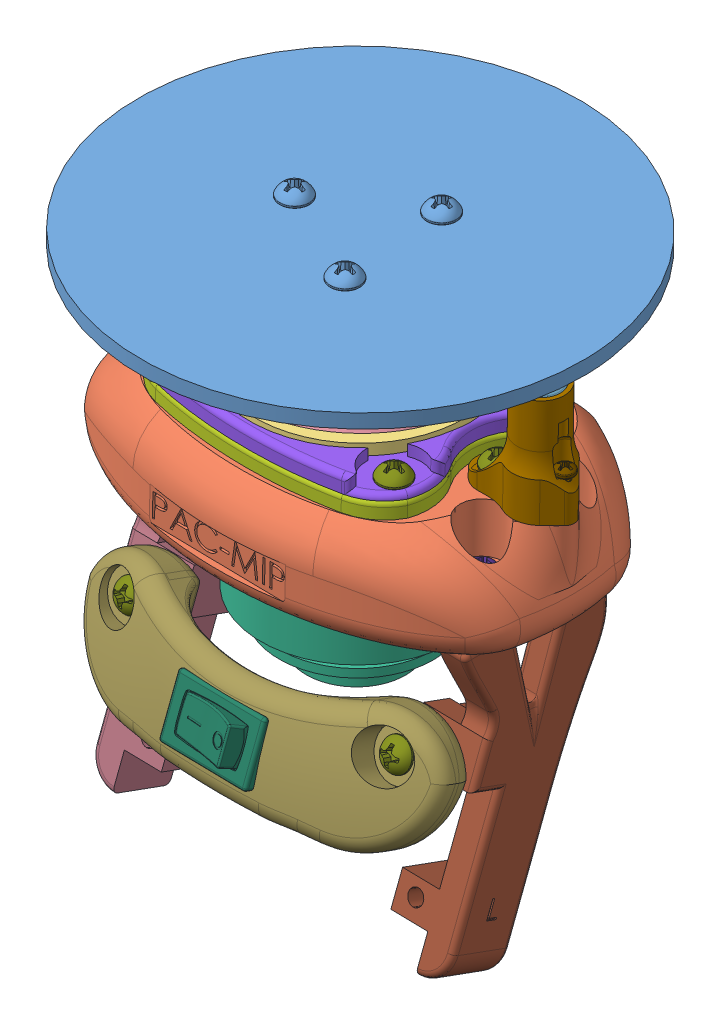
SolidWorks assembly POV, configuration Default. Lengths in mm.
Overall size (86.36 103.02 86.33).
31 component instances, 19 part files, 200 mates.
Components (placement in the parent):
- PCB disk-1: PCB disk [Default] at (29.9915 168.4081 -24.0716) x (-0.082505 0.001098 -0.99659) z (0.996507 -0.012889 -0.082512) size (80 2.79 80)
- Main Frame-1: Main Frame [Default] at (29.7154 147.0599 -24.0722) x (0.999905 -0.012935 0.004708) z (0.004708 -0.00003 -0.999989) size (81.15 20.06 65.6)
- Coil-1: Coil [Default] at (29.8104 154.4093 -24.072) x (0.99142 -0.012822 -0.130081) z (0.13007 -0.001713 0.991503) size (38 2 38)
- Top Coil Mount-1: Top Coil Mount [Default] at (29.8104 154.4093 -24.072) x (0.821748 -0.010613 -0.569753) z (0.012935 0.999916 0.00003) size (43 43 14)
- Motor Hub-1: Motor Hub [Default] at (29.7671 151.0596 -24.0721) x (-0.082505 0.001098 -0.99659) z (0.996507 -0.012889 -0.082512) size (27.61 6.35 25.31)
- Motor_pololu-37D-encoder-2: Motor_pololu-37D-encoder [Default] at (29.6895 145.0601 -24.0723) x (0.495875 -0.006441 0.86837) z (0.012935 0.999916 0.00003) size (34.8 34.8 48.55)
- Motor Mount-1: Motor Mount [Default] at (29.7283 148.0598 -24.0722) x (-0.999905 0.012935 -0.004708) z (-0.004708 0.00003 0.999989) size (48.16 8.83 46)
- Bottom Coil Mount-1: Bottom Coil Mount [Default] at (29.7671 151.0596 -24.0721) x (-0.999905 0.012935 -0.004708) z (-0.004708 0.00003 0.999989) size (48.16 8.83 50.89)
- Magnet Stand-1: Magnet Stand [Default] at (29.7154 147.0599 -24.0722) x (0.999905 -0.012935 0.004708) z (0.004708 -0.00003 -0.999989) size (71.91 19 65.6)
- Coil-2: Coil [Default] at (29.7412 149.0598 -24.0722) x (0.999916 -0.012935 0) z (0 -0.00003 1) size (38 2 38)
- Wire Mount-1: Wire Mount [Default] at (29.9527 165.4084 -24.0717) x (0.821748 -0.010613 -0.569753) z (0.012935 0.999916 0.00003) size (43 47.25 5.24)
- Left Support-1: Left Support [Default] at (28.6976 83.9425 -14.0477) x (0.999905 -0.012935 0.004708) z (0 0.34202 0.939693) size (13.46 57.62 28.85)
- Switch Mount-1: Switch Mount [Default] at (28.9937 75.8569 -66.442) x (0.999905 -0.012935 0.004708) z (0 0.34202 0.939693) size (65.39 22.18 13.95)
- Right Support-1: Right Support [Default] at (-36.2562 84.7828 -14.3535) x (0.999905 -0.012935 0.004708) z (0 0.34202 0.939693) size (13.46 57.62 28.85)
- Magnet-1: Magnet [Default] at (62.7063 161.6344 -23.9173) x (0.999916 -0.012935 0) z (0 -0.00003 1) size (7 2 7)
- Rocker Switch-1: Rocker Switch [Default] at (28.8816 105.0951 1.6459) x (0.013766 0.939604 -0.341988) z (0 0.34202 0.939693) size (10.55 15.93 19.4)
- 90279A110_ZNC PLTD STL ROUND HEAD PHILLIP MACHINE SCREW-1: 90279A110_ZNC PLTD STL ROUND HEAD PHILLIP MACHINE SCREW [90279A110] at (53.2759 108.8307 -7.6756) x (1 0 0) z (0 0.34202 0.939693) size (5.36 5.79 15.41)
- 90279A110_ZNC PLTD STL ROUND HEAD PHILLIP MACHINE SCREW-2: 90279A110_ZNC PLTD STL ROUND HEAD PHILLIP MACHINE SCREW [90279A110] at (5.0205 109.455 -7.9029) x (1 0 0) z (0 0.34202 0.939693) size (5.36 5.79 15.41)
- 90279A110_ZNC PLTD STL ROUND HEAD PHILLIP MACHINE SCREW-3: 90279A110_ZNC PLTD STL ROUND HEAD PHILLIP MACHINE SCREW [90279A110] at (49.6758 148.8015 -10.4782) x (0.999915 -0.012935 0.001662) z (0.012935 0.999916 0.00003) size (5.36 5.79 15.41)
- 90279A110_ZNC PLTD STL ROUND HEAD PHILLIP MACHINE SCREW-4: 90279A110_ZNC PLTD STL ROUND HEAD PHILLIP MACHINE SCREW [90279A110] at (49.8029 148.8006 -37.4779) x (-0.999843 0.012934 0.012152) z (0.012935 0.999916 0.00003) size (5.36 5.79 15.41)
- 90279A110_ZNC PLTD STL ROUND HEAD PHILLIP MACHINE SCREW-5: 90279A110_ZNC PLTD STL ROUND HEAD PHILLIP MACHINE SCREW [90279A110] at (9.6796 149.3189 -10.6665) x (-0.023578 0.000335 -0.999722) z (0.012935 0.999916 0.00003) size (5.36 5.79 15.41)
- 90279A110_ZNC PLTD STL ROUND HEAD PHILLIP MACHINE SCREW-6: 90279A110_ZNC PLTD STL ROUND HEAD PHILLIP MACHINE SCREW [90279A110] at (9.8067 149.3181 -37.6662) x (0.999916 -0.012935 0) z (0.012935 0.999916 0.00003) size (5.36 5.79 15.41)
- 90279A110_ZNC PLTD STL ROUND HEAD PHILLIP MACHINE SCREW-7: 90279A110_ZNC PLTD STL ROUND HEAD PHILLIP MACHINE SCREW [90279A110] at (55.013 146.7327 -23.9531) x (0.999833 -0.012934 -0.012935) z (0.012935 0.999916 0.00003) size (5.36 5.79 15.41)
- 90279A112_ZNC PLTD STL ROUND HEAD PHILLIP MACHINE SCREW-1: 90279A112_ZNC PLTD STL ROUND HEAD PHILLIP MACHINE SCREW [90279A112] at (59.5856 135.6728 -31.4313) x (0.999833 -0.012934 -0.012935) z (0.012935 0.999916 0.00003) size (5.36 5.79 18.6)
- 90279A112_ZNC PLTD STL ROUND HEAD PHILLIP MACHINE SCREW-2: 90279A112_ZNC PLTD STL ROUND HEAD PHILLIP MACHINE SCREW [90279A112] at (59.5149 135.6733 -16.4315) x (0.897955 -0.011603 -0.439934) z (0.012935 0.999916 0.00003) size (5.36 5.79 18.6)
- 90279A112_ZNC PLTD STL ROUND HEAD PHILLIP MACHINE SCREW-3: 90279A112_ZNC PLTD STL ROUND HEAD PHILLIP MACHINE SCREW [90279A112] at (-0.4394 136.4489 -16.7138) x (0.999833 -0.012934 -0.012935) z (0.012935 0.999916 0.00003) size (5.36 5.79 18.6)
- 90279A112_ZNC PLTD STL ROUND HEAD PHILLIP MACHINE SCREW-4: 90279A112_ZNC PLTD STL ROUND HEAD PHILLIP MACHINE SCREW [90279A112] at (-0.3688 136.4484 -31.7136) x (0.999833 -0.012934 -0.012935) z (0.012935 0.999916 0.00003) size (5.36 5.79 18.6)
- 92000A006_18-8 SS METRIC PAN HEAD PHIL MACHINE SCREW-1: 92000A006_18-8 SS METRIC PAN HEAD PHIL MACHINE SCREW [92000A006] at (66.9472 141.5779 -23.8968) x (0.07926 -0.001056 0.996853) z (0.012935 0.999916 0.00003) size (3.2 3.2 13.75)
- 90279A103_ZNC PLTD STL ROUND HEAD PHILLIP MACHINE SCREW-1: 90279A103_ZNC PLTD STL ROUND HEAD PHILLIP MACHINE SCREW [90279A103] at (19.0628 171.0897 -23.1639) x (0.999833 -0.012934 -0.012935) z (0.012935 0.999916 0.00003) size (5.36 5.79 21.79)
- 90279A103_ZNC PLTD STL ROUND HEAD PHILLIP MACHINE SCREW-2: 90279A103_ZNC PLTD STL ROUND HEAD PHILLIP MACHINE SCREW [90279A103] at (34.7192 170.8875 -34.0191) x (0.999833 -0.012934 -0.012935) z (0.012935 0.999916 0.00003) size (5.36 5.79 21.79)
- 90279A103_ZNC PLTD STL ROUND HEAD PHILLIP MACHINE SCREW-3: 90279A103_ZNC PLTD STL ROUND HEAD PHILLIP MACHINE SCREW [90279A103] at (36.2912 170.8666 -15.0315) x (0.999833 -0.012934 -0.012935) z (0.012935 0.999916 0.00003) size (5.36 5.79 21.79)
Mates (geometry in assembly coordinates):
- Coincident87: coincident aligned: plane of ? through (0 0 -29) normal (1 0 0); plane of assembly through (0 0 0) normal (1 0 0)
- Parallel1: parallel aligned: plane of ? through (0 9.05 -29) normal (0 1 0); plane of assembly through (0 0 0) normal (0 1 0)
- Coincident104: coincident aligned: plane of ? through (0 0 -29) normal (1 0 0); plane of assembly through (0 0 0) normal (1 0 0)
- Coincident105: coincident aligned: plane of ? through (0 0 -29) normal (0 1 0); plane of assembly through (0 0 0) normal (0 1 0)
- Coincident106: coincident anti-aligned: plane of ? through (0 9.05 -29) normal (0 1 0); plane of ? through (14.675 9.05 -22.7) normal (0 -1 0)
- Coincident107: coincident aligned: plane of ? through (0 9.05 0) normal (1 0 0); plane of assembly through (0 0 0) normal (1 0 0)
- Coincident112: coincident aligned: plane of ?; plane of assembly through (0 0 0) normal (1 0 0)
- Coincident118: coincident anti-aligned: plane of ? through (-14.605 34.7315 4.0867) normal (0 -0.34202 -0.939693); plane of ? through (14.755 34.708 4.0952) normal (0 0.34202 0.939693)
- Concentric54: concentric anti-aligned: cylinder of ? through (20.955 28.6021 7.6691) axis (0 -0.34202 -0.939693) radius 1.524; cylinder of ? through (20.955 26.3208 1.4013) axis (0 0.34202 0.939693) radius 1.4
- Concentric55: concentric anti-aligned: cylinder of ? through (-20.955 28.6021 7.6691) axis (0 -0.34202 -0.939693) radius 1.524; cylinder of ? through (-20.955 26.3208 1.4013) axis (0 0.34202 0.939693) radius 1.4
- Coincident119: coincident anti-aligned: plane of ? through (-14.605 35.1659 5.2801) normal (0 0.34202 0.939693); plane of ? through (-20.955 28.6021 7.6691) normal (0 -0.34202 -0.939693)
- Coincident120: coincident anti-aligned: plane of ? through (-14.605 35.1659 5.2801) normal (0 0.34202 0.939693); plane of ? through (-24.13 90.6594 -14.9179) normal (0 -0.34202 -0.939693)
- Coincident126: coincident anti-aligned: plane of ? through (27.13 76.9171 -12.3128) normal (0 -0.939693 0.34202); plane of ? through (34.43 81.0214 -1.0365) normal (0 0.939693 -0.34202)
- Parallel5: parallel anti-aligned: plane of ? through (27.13 86.2795 11.9482) normal (-1 0 0); plane of assembly through (0 0 0) normal (1 0 0)
- Coincident127: coincident anti-aligned: plane of ? through (34.43 60.438 21.3538) normal (1 0 0); plane of ? through (34.43 54.647 8.563) normal (-1 0 0)
- Coincident128: coincident anti-aligned: plane of ? through (27.13 81.0214 -1.0365) normal (0 -0.34202 -0.939693); plane of ? through (17.539 58.7046 7.0862) normal (0 0.34202 0.939693)
- Coincident129: coincident anti-aligned: plane of ? through (37.859 54.647 8.563) normal (1 0 0); plane of ? through (37.859 81.1227 -7.4584) normal (-1 0 0)
- Concentric61: concentric anti-aligned: cylinder of ? through (27.13 81.1227 -7.4584) axis (1 0 0) radius 1.25; cylinder of ? through (31.509 81.1227 -7.4584) axis (-1 0 0) radius 2.7813
- Coincident130: coincident anti-aligned: plane of ? through (5.66 104.6001 -6.4259) normal (-1 0 0); plane of ? through (5.66 112.3046 -22.0002) normal (1 0 0)
- Coincident131: coincident anti-aligned: plane of ? through (5.66 100.4958 -17.7022) normal (0 0.34202 0.939693); plane of ? through (-18.089 96.4323 -16.2232) normal (0 -0.34202 -0.939693)
- Distance11: distance = 5.5667 mm anti-aligned: plane of ? through (-21.54 109.8098 -12.5788) normal (0 0.939693 -0.34202); plane of ? through (-22.407 112.3046 -22.0002) normal (0 -0.939693 0.34202)
- Concentric62: concentric anti-aligned: circle of ?; circle of ?
- Coincident133: coincident anti-aligned: plane of ? through (-21.54 103.574 -9.2449) normal (0 -0.34202 -0.939693); plane of ? through (-24.54 106.8629 -10.442) normal (0 0.34202 0.939693)
- Coincident135: coincident anti-aligned: plane of ? through (14.675 30.381 -7.7639) normal (0 0.34202 0.939693); plane of ? through (-20.955 99.653 -32.9768) normal (0 -0.34202 -0.939693)
- Coincident136: coincident aligned: plane of ? through (0 9.05 0) normal (0 0 1); plane of assembly through (0 0 0) normal (0 0 1)
- Coincident141: coincident anti-aligned: plane of ? through (-20.955 99.653 -32.9768) normal (0 -0.34202 -0.939693); plane of ? through (-27.3 89.6662 -29.3419) normal (0 0.34202 0.939693)
- Coincident142: coincident anti-aligned: plane of ?; plane of assembly through (0 0 0) normal (1 0 0)
- Concentric65: concentric aligned: cylinder of ? through (24.13 85.9075 -27.9738) axis (0 -0.34202 -0.939693) radius 1.5875; cylinder of ? through (24.13 85.9075 -27.9738) axis (0 -0.34202 -0.939693) radius 1.65
- Concentric66: concentric aligned: cylinder of ? through (23.5 11.2 -29) axis (0 -1 0) radius 2.25; cylinder of ? through (23.5 9.05 -29) axis (0 -1 0) radius 3.2
- Concentric67: concentric anti-aligned: circle of ?; circle of ?
- Concentric68: concentric anti-aligned: circle of ?; circle of ?
- Coincident144: coincident anti-aligned: line of ? through (26.7627 85.1906 -16.9819) axis (0 -0.939693 0.34202); plane of ? through (26.6447 33.266 1.917) normal (0 0.34202 0.939693)
- Concentric69: concentric aligned: cylinder of ? through (-20.955 26.4303 1.702) axis (0 -0.34202 -0.939693) radius 2.7813; cylinder of ? through (-20.955 23.8502 -5.3868) axis (0 -0.34202 -0.939693) radius 1.5875
- Concentric70: concentric anti-aligned: circle of ?; cylinder of ? through (-20.955 23.8502 -5.3868) axis (0 -0.34202 -0.939693) radius 1.5875
- Coincident145: coincident anti-aligned: plane of ? through (-20.955 24.3888 -3.907) normal (0 -0.34202 -0.939693); plane of ? through (-27.305 100.1703 -31.4892) normal (0 0.34202 0.939693)
- Concentric72: concentric aligned: cylinder of ? through (-24.13 90.6594 -14.9179) axis (0 -0.34202 -0.939693) radius 1.524; cylinder of ? through (-24.13 88.4876 -20.885) axis (0 -0.34202 -0.939693) radius 2.7813
- Concentric73: concentric aligned: cylinder of ? through (-17.7767 1045.8534 -368.7457) axis (0 0.939693 -0.34202) radius 2.6; cylinder of ? through (-17.7767 98.1734 -23.8184) axis (0 0.939693 -0.34202) radius 3.25
- Coincident147: coincident anti-aligned: plane of ? through (-15.9639 105.3887 -24.4611) normal (0 -0.939693 0.34202); plane of ? through (-13.2767 102.5281 -32.3206) normal (0 0.939693 -0.34202)
- Concentric76: concentric aligned: circle of ?; circle of ?
- Coincident150: coincident anti-aligned: plane of ? through (-23.5 16.05 -32.2) normal (0 1 0); plane of ? through (-23.5 16.05 -29) normal (0 -1 0)
- Concentric78: concentric anti-aligned: cylinder of ? through (20.955 19.4039 -17.6028) axis (0 0.34202 0.939693) radius 1.35; cylinder of ? through (20.955 23.8502 -5.3868) axis (0 -0.34202 -0.939693) radius 1.5875
- Concentric79: concentric anti-aligned: cylinder of ? through (-24.13 85.9075 -27.9738) axis (0 -0.34202 -0.939693) radius 1.5875; cylinder of ? through (-24.13 88.1391 -21.8423) axis (0 0.34202 0.939693) radius 2.7813
- Coincident152: coincident anti-aligned: plane of ? through (-21.25 88.6402 -32.161) normal (0 -0.34202 -0.939693); plane of ? through (-24.13 84.8814 -30.7929) normal (0 0.34202 0.939693)
- Tangent1: tangent anti-aligned: cylinder of ? through (5 1.8418 -113.4916) axis (-1 0 0) radius 90.6126; plane of ? through (0 63.0678 -41.2767) normal (0 -0.397857 -0.917447)
- Coincident153: coincident anti-aligned: plane of ? through (-10.5337 28.8071 -1.1093) normal (0 0.939693 -0.34202); plane of ? through (-10.4877 28.6063 -1.661) normal (0 -0.939693 0.34202)
- Distance12: distance = 0.3 mm anti-aligned: plane of ? through (-16.6297 29.5759 1.003) normal (0 0.34202 0.939693); plane of ? through (-16.4377 21.334 4.3221) normal (0 -0.34202 -0.939693)
- Distance13: distance = 0.2 mm anti-aligned: plane of ? through (-4.4377 28.0382 -3.2216) normal (1 0 0); plane of ? through (-4.2377 21.2314 4.0402) normal (-1 0 0)
- Coincident154: coincident anti-aligned: plane of ? through (-19.6703 6.9 -18.3033) normal (0 1 0); plane of ? through (17.25 6.9 2.325) normal (0 -1 0)
- Coincident155: coincident aligned: plane of ? through (28.25 9.05 -6) normal (1 0 0); plane of ? through (28.25 8.05 -14.175) normal (1 0 0)
- Tangent2: tangent anti-aligned: cylinder of ? through (25.475 -18.9495 -17.675) axis (0 1 0) radius 3.5; plane of ? through (23.8 8.05 -14.175) normal (0 0 -1)
- Coincident156: coincident anti-aligned: plane of ? through (-19.6703 6.9 -18.3033) normal (0 1 0); plane of ? through (-17.25 6.9 -60.6) normal (0 -1 0)
- Coincident158: coincident aligned: plane of ? through (-28.25 9.05 -51.8) normal (-1 0 0); plane of ? through (-28.25 8.05 -44.1) normal (-1 0 0)
- Tangent4: tangent anti-aligned: cylinder of ? through (-25.475 6.9 -40.325) axis (0 1 0) radius 3.775; plane of ? through (-23.8 8.05 -44.1) normal (0 0 1)
- Tangent5: tangent anti-aligned: plane of ? through (18.15 31.9484 -23.3393) normal (0 0.939693 -0.34202); cylinder of ? through (-17 31.8137 -26.6332) axis (-1 0 0) radius 1
- Concentric80: concentric aligned: cylinder of ? through (24.13 90.6594 -14.9179) axis (0 -0.34202 -0.939693) radius 1.524; cylinder of ? through (24.13 90.2251 -16.1113) axis (0 -0.34202 -0.939693) radius 1.524
- Parallel6: parallel aligned: plane of ? through (27.305 91.3421 -25.3027) normal (0 0.939693 -0.34202); plane of ? through (27.48 95.4349 -18.0076) normal (0 0.939693 -0.34202)
- Coincident160: coincident anti-aligned: plane of ? through (-14.605 34.7315 4.0867) normal (0 -0.34202 -0.939693); plane of ? through (0 90.2251 -16.1113) normal (0 0.34202 0.939693)
- Parallel7: parallel: plane of ? through (-27.52 111.6031 -55.4912) normal (0 1 0); plane of ? through (5.2597 105.8395 -33.7845) normal (0 -1 0)
- Coincident162: coincident aligned: plane of ? through (-27.52 108.09 -55.4912) normal (0 0 -1); plane of ? through (5.2597 105.8395 -55.4912) normal (0 0 -1)
- Coincident165: coincident anti-aligned: plane of ? through (-27.305 100.1703 -31.4892) normal (0 0.34202 0.939693); plane of ? through (0 86.4461 -26.494) normal (0 -0.34202 -0.939693)
- Concentric82: concentric aligned: cylinder of ? through (-24.13 85.9075 -27.9738) axis (0 -0.34202 -0.939693) radius 1.5875; cylinder of ? through (-24.13 90.2083 -16.1574) axis (0 -0.34202 -0.939693) radius 1.524
- Parallel9: parallel aligned: plane of ? through (-27.3277 76.6103 -96.2197) normal (-1 0 0); plane of ? through (-32.48 67.8753 -49.353) normal (-1 0 0)
- Coincident167: coincident aligned: plane of ? through (32.48 89.199 -18.9304) normal (1 0 0); plane of ? through (32.48 110.392 -7.9437) normal (1 0 0)
- Coincident168: coincident anti-aligned: plane of ? through (27.48 107.892 -18.9304) normal (0 1 0); plane of ? through (0 107.892 -32.9437) normal (0 -1 0)
- Concentric85: concentric aligned: cylinder of ? through (-0.3281 110.392 -25.5046) axis (0 -1 0) radius 16; cylinder of ? through (-0.3281 127.695 -25.5046) axis (0 -1 0) radius 16
- Parallel10: parallel anti-aligned: plane of ? through (32.48 110.392 -7.9437) normal (0 0 1); plane of ? through (0.2469 107.892 -44.7482) normal (0 0 -1)
- Coincident173: coincident anti-aligned: plane of ? through (27.48 107.892 -18.9304) normal (0 1 0); plane of ? through (0.2469 107.892 -23.4587) normal (0 -1 0)
- Concentric87: concentric aligned: cylinder of ? through (29.98 101.892 -35.6921) axis (0 1 0) radius 1.37; cylinder of ? through (29.98 107.892 -35.6921) axis (0 1 0) radius 1.5
- Concentric88: concentric aligned: cylinder of ? through (0.2469 109.892 -23.4587) axis (0 -1 0) radius 16; cylinder of ? through (0.2469 123.792 -23.4587) axis (0 -1 0) radius 16.375
- Coincident175: coincident anti-aligned: plane of ? through (-12.0027 115.6766 -47.2882) normal (0.819152 0.573576 0); plane of ? through (-15.8222 121.1315 -52.3814) normal (-0.819152 -0.573576 0)
- Tangent6: tangent aligned: cylinder of ? through (-12.0027 115.6766 -47.2882) axis (0.819152 0.573576 0) radius 1.9685; face of ?
- Concentric89: concentric aligned: cylinder of ? through (-13.8966 127.348 -42.2082) axis (0 0 -1) radius 1.143; cylinder of ? through (-13.8966 127.348 -44.9582) axis (0 0 -1) radius 1.2
- Coincident176: coincident anti-aligned: plane of ? through (-11.4836 129.761 -49.8282) normal (0 0 1); plane of ? through (-3.6925 127.7565 -49.8282) normal (0 0 -1)
- Concentric90: concentric aligned: cylinder of ? through (0.2469 109.892 -23.4587) axis (0 -1 0) radius 5.5; cylinder of ? through (0.2469 126.792 -23.4587) axis (0 -1 0) radius 5.5
- Coincident177: coincident anti-aligned: plane of ? through (-5.1816 125.792 -22.5748) normal (0 1 0); plane of ? through (0.2469 125.792 -23.4587) normal (0 -1 0)
- Concentric91: concentric aligned: cylinder of ? through (16.1376 115.4175 -48.1432) axis (-0.039999 0.9992 0) radius 0.889; cylinder of ? through (15.7926 124.0361 -48.1432) axis (-0.039999 0.9992 0) radius 0.5468
- Coincident178: coincident anti-aligned: plane of ? through (15.7613 134.203 -49.8282) normal (-0.039999 0.9992 0); plane of ? through (15.3862 134.188 -48.1432) normal (0.039999 -0.9992 0)
- Parallel11: parallel aligned: plane of ? through (12.8882 134.088 -50.6432) normal (0.9992 0.039999 0); plane of ? through (17.3846 134.268 -50.1432) normal (0.9992 0.039999 0)
- Concentric92: concentric anti-aligned: cylinder of ? through (0.2469 109.892 -23.4587) axis (0 -1 0) radius 5.5; cylinder of ? through (0.2469 137.492 -23.4587) axis (0 1 0) radius 5.65
- Coincident182: coincident anti-aligned: plane of ? through (0.2469 141.592 -23.4587) normal (0 1 0); plane of PCB disk-1
- Concentric93: concentric aligned: cylinder of ? through (0.2469 142.792 -23.4587) axis (0 -1 0) radius 16; cylinder of PCB disk-1 through (0.2469 145.332 -23.4587) axis (0 -1 0) radius 40
- Concentric94: concentric aligned: cylinder of ? through (2.288 126.792 -34.2676) axis (0 -1 0) radius 0.75; cylinder of ? through (2.288 141.592 -34.2676) axis (0 -1 0) radius 1.5
- Concentric95: concentric anti-aligned: cylinder of ? through (8.5872 141.592 -16.2866) axis (0 -1 0) radius 1.5; cylinder of PCB disk-1 through (8.5872 134.132 -16.2866) axis (0 1 0) radius 0.75
- Coincident183: coincident anti-aligned: plane of ? through (0.2469 109.892 -23.4587) normal (0 -1 0); plane of ? through (0.2469 109.892 -23.4587) normal (0 1 0)
- Coincident184: coincident anti-aligned: plane of ? through (0.2469 126.792 -23.4587) normal (0 1 0); plane of ? through (0.2469 126.792 -23.4587) normal (0 -1 0)
- Concentric96: concentric anti-aligned: cylinder of ? through (0 150.324 -40.3221) axis (0 -1 0) radius 19.5; cylinder of ? through (0 120.324 -40.3221) axis (0 1 0) radius 17.4
- Coincident187: coincident anti-aligned: plane of ? through (0 150.324 -40.3221) normal (0 -1 0); plane of ? through (0 150.324 -40.3221) normal (0 1 0)
- Concentric99: concentric aligned: cylinder of PCB disk-1 through (0 177.9506 -40.3221) axis (0 -1 0) radius 40; cylinder of ? through (0 157.784 -40.3221) axis (0 -1 0) radius 8.5
- Concentric104: concentric: cylinder of ? through (-24.13 85.9075 -27.9738) axis (0 -0.34202 -0.939693) radius 1.5875; cylinder of ? through (-24.13 90.2083 -16.1574) axis (0 -0.34202 -0.939693) radius 1.524
- Parallel14: parallel: plane of ? through (-27.305 35.1659 5.2801) normal (-1 0 0); plane of ? through (-27.48 89.1822 -18.9765) normal (1 0 0)
- Concentric107: concentric: cylinder of ? through (-29.98 130.6093 -30.818) axis (0 1 0) radius 2.25; cylinder of ? through (-29.98 126.3073 -30.818) axis (0 1 0) radius 1.37
- Coincident194: coincident anti-aligned: plane of ? through (0 132.3073 -38.318) normal (0 -1 0); plane of ? through (-27.48 132.3073 -18.9765) normal (0 1 0)
- Concentric108: concentric aligned: cylinder of ? through (24.13 85.9075 -27.9738) axis (0 -0.34202 -0.939693) radius 1.5875; cylinder of ? through (24.13 90.2251 -16.1113) axis (0 -0.34202 -0.939693) radius 1.524
- Coincident195: coincident anti-aligned: plane of ? through (-14.605 34.7315 4.0867) normal (0 -0.34202 -0.939693); plane of ? through (0 90.2251 -16.1113) normal (0 0.34202 0.939693)
- Concentric109: concentric aligned: cylinder of ? through (-24.13 85.9075 -27.9738) axis (0 -0.34202 -0.939693) radius 1.5875; cylinder of ? through (-24.13 90.2251 -16.1113) axis (0 -0.34202 -0.939693) radius 1.524
- Coincident196: coincident anti-aligned: plane of ? through (-14.605 34.7315 4.0867) normal (0 -0.34202 -0.939693); plane of ? through (0 90.2251 -16.1113) normal (0 0.34202 0.939693)
- Coincident197: coincident anti-aligned: plane of ? through (0 90.2251 -16.1113) normal (0 0.34202 0.939693); plane of ? through (0 116.0857 -25.5238) normal (0 -0.34202 -0.939693)
- Concentric112: concentric aligned: cylinder of ? through (-29.98 130.6261 -32.8221) axis (0 1 0) radius 2.25; cylinder of ? through (-29.98 125.324 -32.8221) axis (0 1 0) radius 1.37
- Parallel15: parallel aligned: plane of ? through (26.7627 85.1906 -16.9819) normal (1 0 0); plane of ? through (32.48 89.199 -18.9304) normal (1 0 0)
- Concentric113: concentric aligned: cylinder of ? through (29.98 130.6261 -32.8221) axis (0 1 0) radius 2.25; cylinder of ? through (29.98 125.324 -32.8221) axis (0 1 0) radius 1.37
- Coincident199: coincident anti-aligned: plane of ? through (0 132.324 -40.3221) normal (0 -1 0); plane of ? through (27.48 132.324 -18.9304) normal (0 1 0)
- Parallel16: parallel anti-aligned: plane of ? through (0 152.324 -40.3221) normal (0 1 0); plane of ? through (0 153.3548 -40.3221) normal (0 -1 0)
- Concentric114: concentric anti-aligned: cylinder of ? through (0 157.784 -40.3221) axis (0 -1 0) radius 8.5; cylinder of ? through (0 158.3548 -40.3221) axis (0 1 0) radius 15.25
- Coincident200: coincident anti-aligned: plane of ? through (27.48 132.324 -18.9304) normal (0 1 0); plane of Main Frame-1
- Coincident201: coincident anti-aligned: plane of Main Frame-1; plane of ? through (0 150.324 -40.3221) normal (0 -1 0)
- Concentric119: concentric aligned: cylinder of Main Frame-1 through (-20 132.324 -53.8221) axis (0 1 0) radius 1.2; cylinder of ? through (-20 150.324 -53.8221) axis (0 1 0) radius 2.25
- Concentric120: concentric aligned: cylinder of Main Frame-1 through (20 132.324 -53.8221) axis (0 1 0) radius 1.2; cylinder of ? through (20 150.324 -53.8221) axis (0 1 0) radius 2.25
- Concentric121: concentric aligned: cylinder of ? through (0 170.8395 -40.3221) axis (0 -1 0) radius 6.985; cylinder of ? through (0 157.784 -40.3221) axis (0 -1 0) radius 2.5
- Concentric122: concentric aligned: cylinder of Main Frame-1 through (0 150.324 -40.3221) axis (0 -1 0) radius 19.5; cylinder of ? through (0 123.324 -40.3221) axis (0 -1 0) radius 14
- Coincident202: coincident anti-aligned: plane of ? through (0 150.324 -40.3221) normal (0 -1 0); plane of ? through (6.175 150.324 -40.3221) normal (0 1 0)
- Concentric124: concentric aligned: cylinder of ? through (0 165.8395 -40.3221) axis (0 -1 0) radius 21.5; cylinder of Coil-1 through (0 161.8395 -40.3221) axis (0 -1 0) radius 19
- Coincident203: coincident anti-aligned: plane of ? through (0 161.8395 -40.3221) normal (0 -1 0); plane of Coil-1
- Concentric125: concentric aligned: cylinder of ? through (0 123.324 -40.3221) axis (0 -1 0) radius 1.5; cylinder of Top Coil Mount-1 through (0 217.0922 -40.3221) axis (0 -1 0) radius 2.5
- Concentric126: concentric aligned: cylinder of ? through (0 123.324 -40.3221) axis (0 -1 0) radius 1.5; cylinder of Motor Hub-1 through (0 210.0922 -40.3221) axis (0 -1 0) radius 13.97
- Concentric127: concentric aligned: cylinder of Top Coil Mount-1 through (34.5053 154.3489 -34.0196) axis (0.012935 0.999916 0.00003) radius 1.5; cylinder of Motor Hub-1 through (34.4619 150.9992 -34.0197) axis (0.012935 0.999916 0.00003) radius 0.635
- Coincident206: coincident anti-aligned: plane of Main Frame-1 through (74.2875 144.4841 -53.4622) normal (0.012935 0.999916 0.00003); plane of Motor Mount-1 through (29.6895 145.0601 -24.0723) normal (-0.012935 -0.999916 -0.00003)
- Concentric130: concentric aligned: cylinder of Main Frame-1 through (49.5183 126.8025 -37.4785) axis (0.012935 0.999916 0.00003) radius 1.2; cylinder of Motor Mount-1 through (49.7512 144.801 -37.478) axis (0.012935 0.999916 0.00003) radius 2.25
- Concentric131: concentric aligned: cylinder of Main Frame-1 through (9.395 127.3207 -10.6671) axis (0.012935 0.999916 0.00003) radius 1.2; cylinder of Motor Mount-1 through (9.6278 145.3192 -10.6666) axis (0.012935 0.999916 0.00003) radius 2.25
- Concentric136: concentric anti-aligned: cylinder of Main Frame-1 through (29.6895 145.0601 -24.0723) axis (-0.012935 -0.999916 -0.00003) radius 19.5; cylinder of Motor_pololu-37D-encoder-2 through (29.3014 115.0626 -24.0732) axis (0.012935 0.999916 0.00003) radius 17.4
- Concentric137: concentric aligned: cylinder of Motor_pololu-37D-encoder-2 through (40.9386 141.9145 -30.5193) axis (0.012935 0.999916 0.00003) radius 1.25; cylinder of Motor Mount-1 through (40.9864 145.6142 -30.5192) axis (0.012935 0.999916 0.00003) radius 3.25
- Coincident207: coincident anti-aligned: plane of Motor_pololu-37D-encoder-2 through (29.6895 145.0601 -24.0723) normal (0.012935 0.999916 0.00003); plane of Motor Mount-1 through (29.6895 145.0601 -24.0723) normal (-0.012935 -0.999916 -0.00003)
- Concentric138: concentric anti-aligned: cylinder of Motor_pololu-37D-encoder-2 through (0 159.324 -40.3221) axis (0 -1 0) radius 1; cylinder of ? through (0 154.7449 -40.3221) axis (0 1 0) radius 1.143
- Coincident208: coincident anti-aligned: plane of Motor Mount-1 through (29.7283 148.0598 -24.0722) normal (0.012935 0.999916 0.00003); plane of Bottom Coil Mount-1 through (29.7283 148.0598 -24.0722) normal (-0.012935 -0.999916 -0.00003)
- Concentric139: concentric aligned: cylinder of Motor Mount-1 through (9.755 145.3184 -37.6663) axis (0.012935 0.999916 0.00003) radius 2.25; cylinder of Bottom Coil Mount-1 through (9.7938 148.3181 -37.6662) axis (0.012935 0.999916 0.00003) radius 2.25
- Concentric140: concentric aligned: cylinder of Motor Mount-1 through (49.624 144.8018 -10.4783) axis (0.012935 0.999916 0.00003) radius 2.25; cylinder of Bottom Coil Mount-1 through (49.6629 147.8016 -10.4782) axis (0.012935 0.999916 0.00003) radius 2.25
- Coincident209: coincident anti-aligned: plane of Main Frame-1 through (74.2875 144.4841 -53.4622) normal (0.012935 0.999916 0.00003); plane of Magnet Stand-1 through (57.6885 144.6978 -20.1417) normal (-0.012935 -0.999916 -0.00003)
- Concentric141: concentric anti-aligned: cylinder of Main Frame-1 through (54.8189 131.7339 -23.9536) axis (0.012935 0.999916 0.00003) radius 1.2; cylinder of Magnet Stand-1 through (55 145.7327 -23.9531) axis (-0.012935 -0.999916 -0.00003) radius 1.7
- Concentric142: concentric anti-aligned: cylinder of Main Frame-1 through (66.8178 131.5787 -23.8971) axis (0.012935 0.999916 0.00003) radius 0.5; cylinder of Magnet Stand-1 through (67.18 159.5764 -23.8962) axis (-0.012935 -0.999916 -0.00003) radius 0.975
- Coincident210: coincident anti-aligned: plane of Bottom Coil Mount-1 through (29.7412 149.0598 -24.0722) normal (0.012935 0.999916 0.00003); plane of Coil-2 through (29.7412 149.0598 -24.0722) normal (-0.012935 -0.999916 -0.00003)
- Concentric143: concentric anti-aligned: cylinder of Bottom Coil Mount-1 through (29.7412 149.0598 -24.0722) axis (0.012935 0.999916 0.00003) radius 20; cylinder of Coil-2 through (29.7671 151.0596 -24.0721) axis (-0.012935 -0.999916 -0.00003) radius 15
- Concentric144: concentric aligned: cylinder of Coil-1 through (29.8363 156.4091 -24.0719) axis (-0.012935 -0.999916 -0.00003) radius 15; cylinder of Top Coil Mount-1 through (29.8363 156.4091 -24.0719) axis (-0.012935 -0.999916 -0.00003) radius 20
- Concentric145: concentric anti-aligned: cylinder of Motor Hub-1 through (29.8493 157.4091 -24.0719) axis (0.012935 0.999916 0.00003) radius 0.5; cylinder of Motor_pololu-37D-encoder-2 through (29.8059 154.0593 -24.072) axis (-0.012935 -0.999916 -0.00003) radius 1
- Concentric146: concentric anti-aligned: cylinder of Top Coil Mount-1 through (29.9915 168.4081 -24.0716) axis (-0.012935 -0.999916 -0.00003) radius 2.5; cylinder of Motor Hub-1 through (29.8493 157.4091 -24.0719) axis (0.012935 0.999916 0.00003) radius 0.5
- Coincident213: coincident anti-aligned: plane of Coil-1 through (29.8363 156.4091 -24.0719) normal (0.012935 0.999916 0.00003); plane of Top Coil Mount-1 through (29.8363 156.4091 -24.0719) normal (-0.012935 -0.999916 -0.00003)
- Coincident215: coincident anti-aligned: plane of Top Coil Mount-1 through (29.8493 157.4091 -24.0719) normal (-0.012935 -0.999916 -0.00003); plane of Motor Hub-1 through (29.8493 157.4091 -24.0719) normal (0.012935 0.999916 0.00003)
- Coincident216: coincident anti-aligned: plane of Motor Hub-1 through (29.7671 151.0596 -24.0721) normal (-0.012935 -0.999916 -0.00003); plane of Bottom Coil Mount-1 through (29.7671 151.0596 -24.0721) normal (0.012935 0.999916 0.00003)
- Coincident218: coincident anti-aligned: plane of Top Coil Mount-1 through (10.5231 168.6601 -26.7945) normal (-0.964628 0.012487 -0.263318); plane of Wire Mount-1 through (11.1166 163.6521 -29.2064) normal (0.964628 -0.012487 0.263318)
- Coincident219: coincident anti-aligned: plane of Top Coil Mount-1 through (34.2707 168.3534 -43.2598) normal (0.09179 -0.001157 -0.995778); plane of Wire Mount-1 through (31.7168 163.386 -43.4894) normal (-0.09179 0.001157 0.995778)
- Concentric147: concentric anti-aligned: cylinder of Top Coil Mount-1 through (15.8603 165.5908 -27.5039) axis (-0.964628 0.012487 -0.263318) radius 1.37; cylinder of Wire Mount-1 through (0.238 165.793 -31.7684) axis (0.964628 -0.012487 0.263318) radius 1.5
- Coincident220: coincident anti-aligned: plane of PCB disk-1 through (29.9915 168.4081 -24.0716) normal (-0.012935 -0.999916 -0.00003); plane of Top Coil Mount-1 through (29.9915 168.4081 -24.0716) normal (0.012935 0.999916 0.00003)
- Concentric148: concentric aligned: cylinder of ? through (24.13 102.8528 -44.408) axis (0 0.34202 0.939693) radius 1.525; cylinder of ? through (24.13 107.6908 -31.1158) axis (0 0.34202 0.939693) radius 1.525
- Concentric149: concentric aligned: cylinder of ? through (24.13 85.9075 -27.9738) axis (0 -0.34202 -0.939693) radius 1.5875; cylinder of Left Support-1 through (24.13 90.2083 -16.1574) axis (0 -0.34202 -0.939693) radius 1.37
- Coincident221: coincident anti-aligned: plane of ? through (-27.305 100.1703 -31.4892) normal (0 0.34202 0.939693); plane of Left Support-1 through (-0.154 86.4461 -26.494) normal (0 -0.34202 -0.939693)
- Concentric151: concentric aligned: cylinder of Main Frame-1 through (59.3766 124.9762 -16.4318) axis (0.012935 0.999916 0.00003) radius 2.25; cylinder of Left Support-1 through (59.308 119.6746 -16.432) axis (0.012935 0.999916 0.00003) radius 1.37
- Concentric152: concentric aligned: cylinder of Main Frame-1 through (59.4472 124.9758 -31.4317) axis (0.012935 0.999916 0.00003) radius 2.25; cylinder of Left Support-1 through (59.3786 119.6742 -31.4318) axis (0.012935 0.999916 0.00003) radius 1.37
- Coincident224: coincident anti-aligned: plane of ? through (-27.305 100.1703 -31.4892) normal (0 0.34202 0.939693); plane of ? through (0 86.4461 -26.494) normal (0 -0.34202 -0.939693)
- Concentric153: concentric anti-aligned: cylinder of ? through (24.13 85.9075 -27.9738) axis (0 -0.34202 -0.939693) radius 1.5875; cylinder of ? through (24.13 86.4461 -26.494) axis (0 0.34202 0.939693) radius 1.524
- Parallel18: parallel aligned: plane of ? through (27.305 35.1659 5.2801) normal (1 0 0); plane of ? through (32.48 134.2419 -45.4225) normal (1 0 0)
- Concentric154: concentric aligned: cylinder of ? through (-24.13 102.8528 -44.408) axis (0 0.34202 0.939693) radius 1.525; cylinder of ? through (-24.13 107.6908 -31.1158) axis (0 0.34202 0.939693) radius 1.525
- Concentric155: concentric aligned: cylinder of Left Support-1 through (53.2759 97.7714 -38.0608) axis (0 0.34202 0.939693) radius 1.37; cylinder of Switch Mount-1 through (53.2759 103.7004 -21.771) axis (0 0.34202 0.939693) radius 1.525
- Concentric157: concentric aligned: cylinder of ? through (-24.13 102.8528 -44.408) axis (0 0.34202 0.939693) radius 1.525; cylinder of Switch Mount-1 through (-24.13 109.2562 -26.8149) axis (0 0.34202 0.939693) radius 1.525
- Concentric158: concentric aligned: cylinder of ? through (-24.13 85.9075 -27.9738) axis (0 -0.34202 -0.939693) radius 1.5875; cylinder of Right Support-1 through (-24.13 90.2083 -16.1574) axis (0 -0.34202 -0.939693) radius 1.37
- Parallel20: parallel aligned: plane of ? through (-27.3277 76.6103 -96.2197) normal (-1 0 0); plane of Right Support-1
- Coincident230: coincident anti-aligned: plane of ? through (-27.305 100.1703 -31.4892) normal (0 0.34202 0.939693); plane of Right Support-1 through (0.154 86.4461 -26.494) normal (0 -0.34202 -0.939693)
- Concentric159: concentric aligned: cylinder of PCB disk-1 through (36.1618 160.8674 -15.0318) axis (0.012935 0.999916 0.00003) radius 0.75; cylinder of Top Coil Mount-1 through (36.0772 154.328 -15.032) axis (0.012935 0.999916 0.00003) radius 1.5
- Concentric160: concentric anti-aligned: cylinder of PCB disk-1 through (30.0244 170.9479 -24.0715) axis (-0.012935 -0.999916 -0.00003) radius 40; circle of Top Coil Mount-1
- Concentric161: concentric anti-aligned: cylinder of Magnet Stand-1 through (62.7063 161.6344 -23.9173) axis (0.012935 0.999916 0.00003) radius 3.5; cylinder of Magnet-1 through (62.7322 163.6342 -23.9173) axis (-0.012935 -0.999916 -0.00003) radius 3.5
- Coincident231: coincident anti-aligned: plane of Magnet Stand-1 through (62.7063 161.6344 -23.9173) normal (0.012935 0.999916 0.00003); plane of Magnet-1 through (62.7063 161.6344 -23.9173) normal (-0.012935 -0.999916 -0.00003)
- Coincident232: coincident anti-aligned: plane of Switch Mount-1 through (36.6103 113.1748 11.4947) normal (-0.013766 -0.939604 0.341988); plane of Rocker Switch-1 through (22.3418 105.7774 -9.4038) normal (0.013766 0.939604 -0.341988)
- Coincident233: coincident anti-aligned: plane of Main Frame-1 through (29.4567 127.0616 -24.0728) normal (-0.012935 -0.999916 -0.00003); plane of Right Support-1 through (1.9321 127.4174 -14.175) normal (0.012935 0.999916 0.00003)
- Concentric162: concentric aligned: cylinder of Switch Mount-1 through (5.0205 104.3247 -21.9983) axis (0 0.34202 0.939693) radius 1.525; cylinder of Right Support-1 through (5.0205 98.3957 -38.288) axis (0 0.34202 0.939693) radius 1.37
- Parallel21: parallel anti-aligned: plane of Right Support-1 through (29.0056 84.9646 -11.2271) normal (0 0.34202 0.939693); plane of Rocker Switch-1 through (36.7315 99.755 2.0127) normal (0 -0.34202 -0.939693)
- Distance14: distance = 17.5 mm anti-aligned: plane of Rocker Switch-1 through (36.7315 99.755 2.0127) normal (0 -0.34202 -0.939693); plane of Right Support-1 through (29.0056 84.9646 -11.2271) normal (0 0.34202 0.939693)
- Distance15: distance = 26.1198 mm aligned: plane of Rocker Switch-1 through (35.455 103.8618 -10.835) normal (0.999905 -0.012935 0.004708); plane of Left Support-1 through (61.3285 83.5203 -13.894) normal (0.999905 -0.012935 0.004708)
- Concentric164: concentric aligned: cylinder of Main Frame-1 through (-0.5778 125.7518 -16.7141) axis (0.012935 0.999916 0.00003) radius 2.25; cylinder of Right Support-1 through (-0.6464 120.4502 -16.7143) axis (0.012935 0.999916 0.00003) radius 1.37
- Coincident234: coincident anti-aligned: plane of Switch Mount-1 through (29.1681 108.2801 -14.3924) normal (0 -0.34202 -0.939693); plane of Right Support-1 through (29.0056 86.6747 -6.5287) normal (0 0.34202 0.939693)
- Concentric165: concentric anti-aligned: cylinder of Switch Mount-1 through (5.0205 109.455 -7.9029) axis (0 0.34202 0.939693) radius 4.1601; cylinder of 90279A110_ZNC PLTD STL ROUND HEAD PHILLIP MACHINE SCREW-2 through (5.0205 110.2021 -5.8502) axis (0 -0.34202 -0.939693) radius 2.6797
- Coincident235: coincident anti-aligned: plane of Switch Mount-1 through (5.0205 109.455 -7.9029) normal (0 0.34202 0.939693); plane of 90279A110_ZNC PLTD STL ROUND HEAD PHILLIP MACHINE SCREW-2 through (5.0205 109.455 -7.9029) normal (0 -0.34202 -0.939693)
- Concentric166: concentric anti-aligned: cylinder of Switch Mount-1 through (53.2759 108.8307 -7.6756) axis (0 0.34202 0.939693) radius 4.1601; cylinder of 90279A110_ZNC PLTD STL ROUND HEAD PHILLIP MACHINE SCREW-1 through (53.2759 109.5778 -5.623) axis (0 -0.34202 -0.939693) radius 2.6797
- Coincident236: coincident anti-aligned: plane of Switch Mount-1 through (53.2759 108.8307 -7.6756) normal (0 0.34202 0.939693); plane of 90279A110_ZNC PLTD STL ROUND HEAD PHILLIP MACHINE SCREW-1 through (53.2759 108.8307 -7.6756) normal (0 -0.34202 -0.939693)
- Coincident237: coincident anti-aligned: plane of Bottom Coil Mount-1 through (29.7412 149.0598 -24.0722) normal (0.012935 0.999916 0.00003); plane of 90279A110_ZNC PLTD STL ROUND HEAD PHILLIP MACHINE SCREW-6 through (9.8067 149.3181 -37.6662) normal (-0.012935 -0.999916 -0.00003)
- Concentric167: concentric anti-aligned: cylinder of Bottom Coil Mount-1 through (9.7938 148.3181 -37.6662) axis (0.012935 0.999916 0.00003) radius 2.25; cylinder of 90279A110_ZNC PLTD STL ROUND HEAD PHILLIP MACHINE SCREW-6 through (9.835 151.5023 -37.6661) axis (-0.012935 -0.999916 -0.00003) radius 2.6797
- Concentric168: concentric anti-aligned: cylinder of Bottom Coil Mount-1 through (9.6666 148.319 -10.6665) axis (0.012935 0.999916 0.00003) radius 2.25; cylinder of 90279A110_ZNC PLTD STL ROUND HEAD PHILLIP MACHINE SCREW-5 through (9.7078 151.5031 -10.6664) axis (-0.012935 -0.999916 -0.00003) radius 2.6797
- Coincident238: coincident anti-aligned: plane of Bottom Coil Mount-1 through (29.7412 149.0598 -24.0722) normal (0.012935 0.999916 0.00003); plane of 90279A110_ZNC PLTD STL ROUND HEAD PHILLIP MACHINE SCREW-5 through (9.6796 149.3189 -10.6665) normal (-0.012935 -0.999916 -0.00003)
- Coincident239: coincident anti-aligned: plane of Bottom Coil Mount-1 through (29.7412 149.0598 -24.0722) normal (0.012935 0.999916 0.00003); plane of 90279A110_ZNC PLTD STL ROUND HEAD PHILLIP MACHINE SCREW-3 through (49.6758 148.8015 -10.4782) normal (-0.012935 -0.999916 -0.00003)
- Concentric169: concentric anti-aligned: cylinder of Bottom Coil Mount-1 through (49.6629 147.8016 -10.4782) axis (0.012935 0.999916 0.00003) radius 2.25; cylinder of 90279A110_ZNC PLTD STL ROUND HEAD PHILLIP MACHINE SCREW-3 through (49.704 150.9857 -10.4781) axis (-0.012935 -0.999916 -0.00003) radius 2.6797
- Concentric170: concentric anti-aligned: cylinder of Bottom Coil Mount-1 through (49.79 147.8007 -37.4779) axis (0.012935 0.999916 0.00003) radius 2.25; cylinder of 90279A110_ZNC PLTD STL ROUND HEAD PHILLIP MACHINE SCREW-4 through (49.8312 150.9849 -37.4778) axis (-0.012935 -0.999916 -0.00003) radius 2.6797
- Coincident241: coincident anti-aligned: plane of Bottom Coil Mount-1 through (29.7412 149.0598 -24.0722) normal (0.012935 0.999916 0.00003); plane of 90279A110_ZNC PLTD STL ROUND HEAD PHILLIP MACHINE SCREW-4 through (49.8029 148.8006 -37.4779) normal (-0.012935 -0.999916 -0.00003)
- Concentric171: concentric aligned: cylinder of Magnet Stand-1 through (55 145.7327 -23.9531) axis (-0.012935 -0.999916 -0.00003) radius 1.7; cylinder of 90279A110_ZNC PLTD STL ROUND HEAD PHILLIP MACHINE SCREW-7 through (55.0412 148.9169 -23.953) axis (-0.012935 -0.999916 -0.00003) radius 2.6797
- Coincident242: coincident anti-aligned: plane of Magnet Stand-1 through (55.013 146.7327 -23.9531) normal (0.012935 0.999916 0.00003); plane of 90279A110_ZNC PLTD STL ROUND HEAD PHILLIP MACHINE SCREW-7 through (55.013 146.7327 -23.9531) normal (-0.012935 -0.999916 -0.00003)
- Concentric172: concentric anti-aligned: cylinder of Main Frame-1 through (59.5856 135.6728 -31.4313) axis (0.012935 0.999916 0.00003) radius 4; cylinder of 90279A112_ZNC PLTD STL ROUND HEAD PHILLIP MACHINE SCREW-1 through (59.6138 137.857 -31.4313) axis (-0.012935 -0.999916 -0.00003) radius 2.6797
- Concentric173: concentric anti-aligned: cylinder of Main Frame-1 through (59.5149 135.6733 -16.4315) axis (0.012935 0.999916 0.00003) radius 4; cylinder of 90279A112_ZNC PLTD STL ROUND HEAD PHILLIP MACHINE SCREW-2 through (59.5432 137.8575 -16.4314) axis (-0.012935 -0.999916 -0.00003) radius 2.6797
- Coincident243: coincident anti-aligned: plane of Main Frame-1 through (59.5856 135.6728 -31.4313) normal (0.012935 0.999916 0.00003); plane of 90279A112_ZNC PLTD STL ROUND HEAD PHILLIP MACHINE SCREW-1 through (59.5856 135.6728 -31.4313) normal (-0.012935 -0.999916 -0.00003)
- Coincident244: coincident anti-aligned: plane of Main Frame-1 through (-0.3688 136.4484 -31.7136) normal (0.012935 0.999916 0.00003); plane of 90279A112_ZNC PLTD STL ROUND HEAD PHILLIP MACHINE SCREW-4 through (-0.3688 136.4484 -31.7136) normal (-0.012935 -0.999916 -0.00003)
- Coincident245: coincident anti-aligned: plane of Main Frame-1 through (-0.4394 136.4489 -16.7138) normal (0.012935 0.999916 0.00003); plane of 90279A112_ZNC PLTD STL ROUND HEAD PHILLIP MACHINE SCREW-3 through (-0.4394 136.4489 -16.7138) normal (-0.012935 -0.999916 -0.00003)
- Concentric174: concentric anti-aligned: cylinder of Main Frame-1 through (-0.5778 125.7518 -16.7141) axis (0.012935 0.999916 0.00003) radius 2.25; cylinder of 90279A112_ZNC PLTD STL ROUND HEAD PHILLIP MACHINE SCREW-3 through (-0.4111 138.6331 -16.7137) axis (-0.012935 -0.999916 -0.00003) radius 2.6797
- Concentric175: concentric anti-aligned: cylinder of Main Frame-1 through (-0.5071 125.7514 -31.714) axis (0.012935 0.999916 0.00003) radius 2.25; cylinder of 90279A112_ZNC PLTD STL ROUND HEAD PHILLIP MACHINE SCREW-4 through (-0.3405 138.6326 -31.7136) axis (-0.012935 -0.999916 -0.00003) radius 2.6797
- Coincident246: coincident anti-aligned: plane of Main Frame-1 through (59.5149 135.6733 -16.4315) normal (0.012935 0.999916 0.00003); plane of 90279A112_ZNC PLTD STL ROUND HEAD PHILLIP MACHINE SCREW-2 through (59.5149 135.6733 -16.4315) normal (-0.012935 -0.999916 -0.00003)
- Concentric176: concentric: cylinder of Magnet Stand-1 through (67.18 159.5764 -23.8962) axis (-0.012935 -0.999916 -0.00003) radius 0.975; cylinder of ? through (66.9472 141.5779 -23.8968) axis (-0.012935 -0.999916 -0.00003) radius 2
- Coincident247: coincident anti-aligned: plane of Magnet Stand-1 through (67.0765 151.577 -23.8965) normal (0.012935 0.999916 0.00003); plane of ? through (67.0765 151.577 -23.8965) normal (-0.012935 -0.999916 -0.00003)
- Concentric177: concentric aligned: cylinder of Magnet Stand-1 through (67.18 159.5764 -23.8962) axis (-0.012935 -0.999916 -0.00003) radius 0.975; cylinder of 92000A006_18-8 SS METRIC PAN HEAD PHIL MACHINE SCREW-1 through (66.9472 141.5779 -23.8968) axis (-0.012935 -0.999916 -0.00003) radius 1.6
- Coincident248: coincident anti-aligned: plane of Magnet Stand-1 through (67.0765 151.577 -23.8965) normal (0.012935 0.999916 0.00003); plane of 92000A006_18-8 SS METRIC PAN HEAD PHIL MACHINE SCREW-1 through (67.0765 151.577 -23.8965) normal (-0.012935 -0.999916 -0.00003)
- Concentric178: concentric: cylinder of PCB disk-1 through (18.9335 161.0905 -23.1642) axis (0.012935 0.999916 0.00003) radius 0.75; cylinder of ? through (19.0911 173.2739 -23.1638) axis (-0.012935 -0.999916 -0.00003) radius 2.6797
- Coincident249: coincident anti-aligned: plane of PCB disk-1 through (30.0244 170.9479 -24.0715) normal (0.012935 0.999916 0.00003); plane of ? through (19.0628 171.0897 -23.1639) normal (-0.012935 -0.999916 -0.00003)
- Concentric179: concentric anti-aligned: cylinder of PCB disk-1 through (18.9335 161.0905 -23.1642) axis (0.012935 0.999916 0.00003) radius 0.75; cylinder of 90279A103_ZNC PLTD STL ROUND HEAD PHILLIP MACHINE SCREW-1 through (19.0911 173.2739 -23.1638) axis (-0.012935 -0.999916 -0.00003) radius 2.6797
- Concentric180: concentric anti-aligned: cylinder of PCB disk-1 through (36.1618 160.8674 -15.0318) axis (0.012935 0.999916 0.00003) radius 0.75; cylinder of 90279A103_ZNC PLTD STL ROUND HEAD PHILLIP MACHINE SCREW-3 through (36.3194 173.0508 -15.0315) axis (-0.012935 -0.999916 -0.00003) radius 2.6797
- Concentric181: concentric anti-aligned: cylinder of PCB disk-1 through (34.5899 160.8883 -34.0194) axis (0.012935 0.999916 0.00003) radius 0.75; cylinder of 90279A103_ZNC PLTD STL ROUND HEAD PHILLIP MACHINE SCREW-2 through (34.7475 173.0717 -34.019) axis (-0.012935 -0.999916 -0.00003) radius 2.6797
- Coincident250: coincident anti-aligned: plane of PCB disk-1 through (30.0244 170.9479 -24.0715) normal (0.012935 0.999916 0.00003); plane of 90279A103_ZNC PLTD STL ROUND HEAD PHILLIP MACHINE SCREW-3 through (36.2912 170.8666 -15.0315) normal (-0.012935 -0.999916 -0.00003)
- Coincident251: coincident anti-aligned: plane of PCB disk-1 through (30.0244 170.9479 -24.0715) normal (0.012935 0.999916 0.00003); plane of 90279A103_ZNC PLTD STL ROUND HEAD PHILLIP MACHINE SCREW-2 through (34.7192 170.8875 -34.0191) normal (-0.012935 -0.999916 -0.00003)
- Coincident252: coincident anti-aligned: plane of PCB disk-1 through (30.0244 170.9479 -24.0715) normal (0.012935 0.999916 0.00003); plane of 90279A103_ZNC PLTD STL ROUND HEAD PHILLIP MACHINE SCREW-1 through (19.0628 171.0897 -23.1639) normal (-0.012935 -0.999916 -0.00003)
